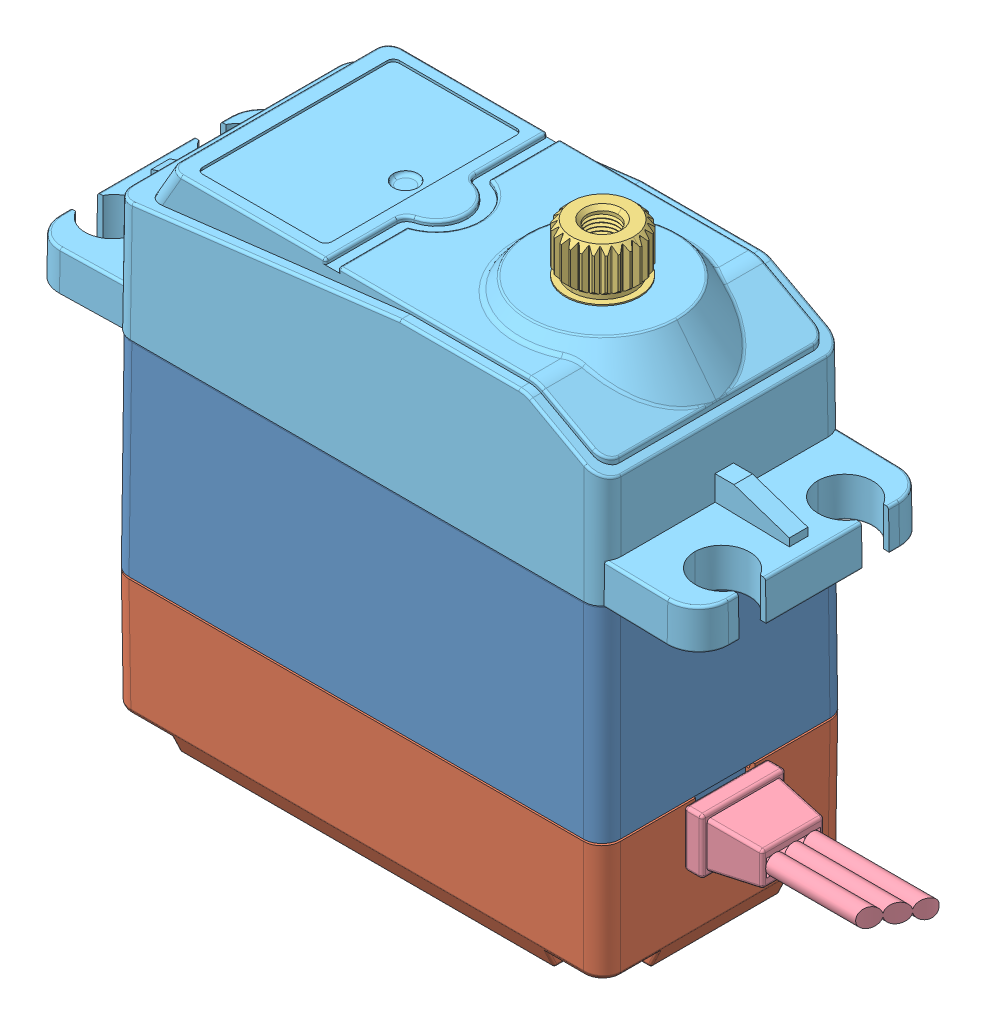
SolidWorks assembly 单轴舵机。, configuration 默认. Lengths in mm.
Overall size (62.21 45.5 20.07).
7 component instances, 5 part files, 0 mates.
Components (placement in the parent):
- 单轴舵机.STEP-1: 单轴舵机.STEP [默认] at origin size (62.21 45.5 20.07)
  - DS3218(2)^单轴舵机.STEP-1: DS3218(2)^单轴舵机.STEP [默认] at (22.0661 -25.9401 -11.5148) size (62.21 45.5 20.07)
    - ZK^DS3218(2)_单轴舵机.STEP-1: ZK^DS3218(2)_单轴舵机.STEP [默认] at origin size (39.96 19.01 20.06)
    - DG-SZ^DS3218(2)_单轴舵机.STEP-1: DG-SZ^DS3218(2)_单轴舵机.STEP [默认] at origin size (39.97 10.96 20.07)
    - GE^DS3218(2)_单轴舵机.STEP-1: GE^DS3218(2)_单轴舵机.STEP [默认] at (10 10.9 0) x (1 0 0) z (0 -1 0) size (17.3 17.3 15.8)
    - XIANTAO^DS3218(2)_单轴舵机.STEP-1: XIANTAO^DS3218(2)_单轴舵机.STEP [默认] at (18.2007 -11.45 -0.1) size (18.31 4.5 6.8)
    - SG-JIANRONG-MG996^DS3218(2)_单轴舵机.STEP-1: SG-JIANRONG-MG996^DS3218(2)_单轴舵机.STEP [默认] at origin size (54.4 13.92 19.9)
